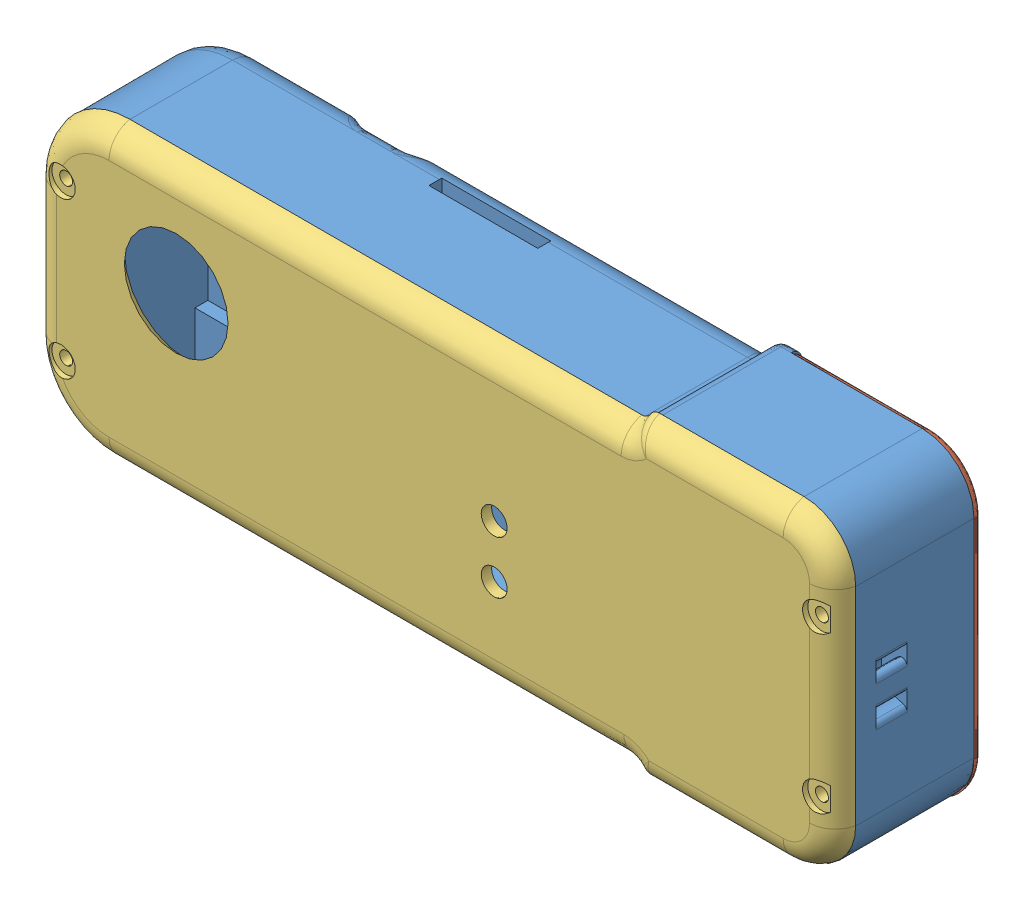
SolidWorks assembly Assem2, configuration Default. Lengths in mm.
Overall size (155.3 60.67 29.23).
3 component instances, 3 part files, 0 mates.
Components (placement in the parent):
- controller_kaj-1: controller_kaj [Default] at (-36.4324 57.8639 110.7183) size (155.08 60 25)
- controller_kaj_battery-1: controller_kaj_battery [Default] at (118.5089 117.4781 112.7357) x (0 -1 0) z (0 0 -1) size (60 37.25 4)
- controller_kaj_lid-1: controller_kaj_lid [Default] at (118.7949 58.14 139.7786) x (-1 0 0) z (0 0 -1) size (155 60.01 4.17)
